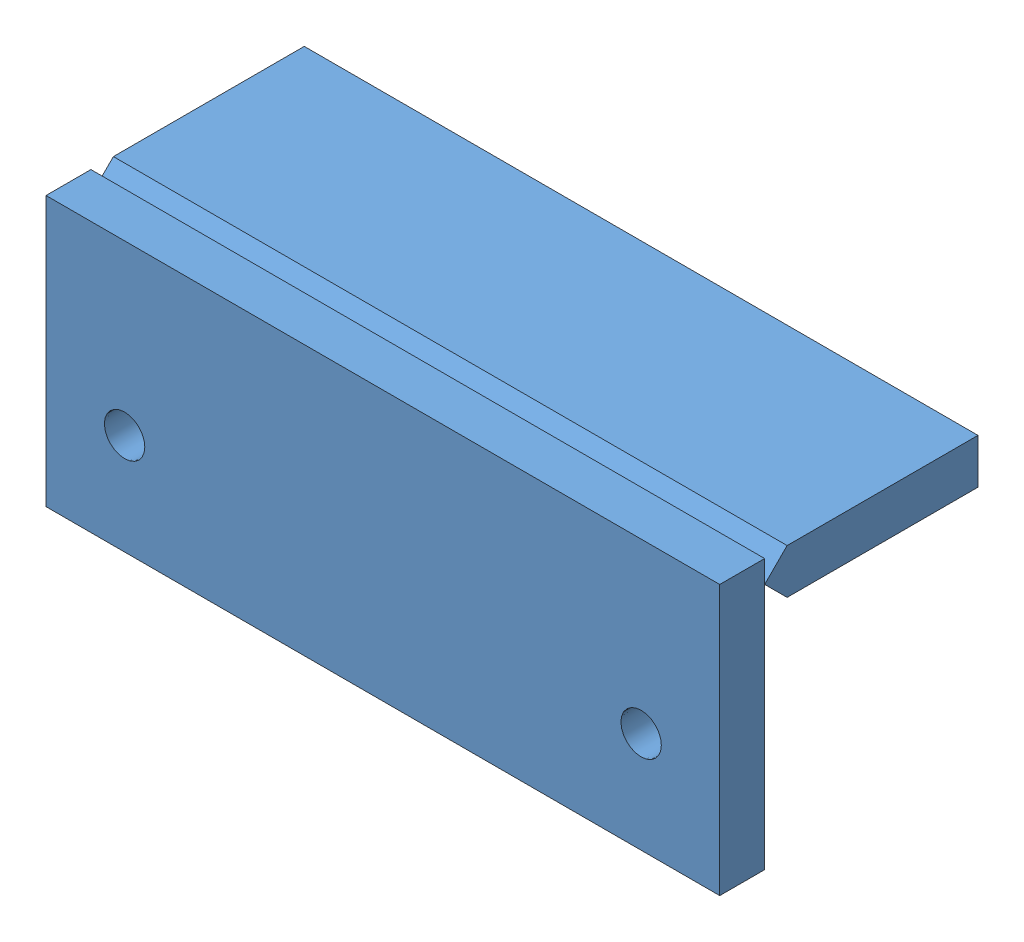
SolidWorks assembly Bearing_fixtur, configuration Default. Lengths in mm.
Overall size (300 120 115).
4 component instances, 2 part files, 9 mates.
Components (placement in the parent):
- 20mm_plate-1: 20mm_plate [Default] at origin size (300 120 20)
- 20mm_plate-2: 20mm_plate [smal] at (0 100 0) x (1 0 0) z (0 1 0) size (300 95 20)
- 12mm_plate-1: 12mm_plate [Default] at (228 80 0) x (0 -1 0) z (1 0 0) size (90 90 12)
- 12mm_plate-2: 12mm_plate [Default] at (60 80 0) x (0 -1 0) z (1 0 0) size (90 90 12)
Mates (geometry in assembly coordinates):
- Coincident1: coincident aligned: plane of 20mm_plate-1 through (300 0 20) normal (1 0 0); plane of 20mm_plate-2 through (300 120 0) normal (1 0 0)
- Coincident2: coincident anti-aligned: plane of 20mm_plate-1 through (0 0 0) normal (0 0 -1); line of 20mm_plate-2 through (300 110 0) axis (-1 0 0)
- Coincident3: coincident aligned: plane of 20mm_plate-1 through (0 120 20) normal (0 1 0); plane of 20mm_plate-2 through (0 120 0) normal (0 1 0)
- Coincident4: coincident anti-aligned: plane of 20mm_plate-1 through (0 0 0) normal (0 0 -1); plane of 12mm_plate-1 through (240 10 0) normal (0 0 1)
- Coincident5: coincident anti-aligned: plane of 20mm_plate-2 through (0 100 0) normal (0 -1 0); plane of 12mm_plate-1 through (240 100 -20) normal (0 1 0)
- Coincident6: coincident anti-aligned: plane of 20mm_plate-2 through (0 100 0) normal (0 -1 0); plane of 12mm_plate-2 through (72 100 -20) normal (0 1 0)
- Coincident7: coincident anti-aligned: plane of 20mm_plate-1 through (0 0 0) normal (0 0 -1); plane of 12mm_plate-2 through (72 10 0) normal (0 0 1)
- Distance1: distance = 60 mm aligned: plane of 12mm_plate-1 through (240 80 0) normal (1 0 0); plane of 20mm_plate-2 through (300 120 0) normal (1 0 0)
- Distance2: distance = 60 mm aligned: plane of 12mm_plate-2 through (60 80 0) normal (-1 0 0); plane of 20mm_plate-2 through (0 120 0) normal (-1 0 0)
